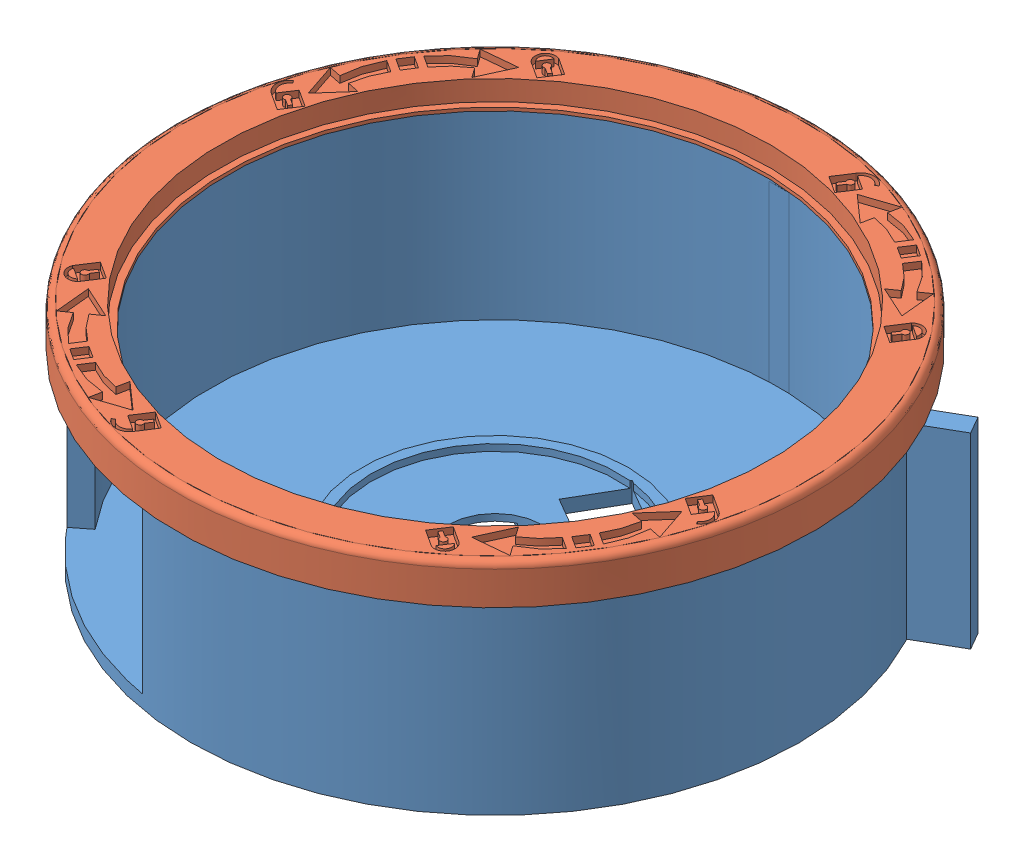
SolidWorks assembly shel ass, configuration Default. Lengths in mm.
Overall size (131.41 34.3 131.41).
2 component instances, 2 part files, 1 mates.
Components (placement in the parent):
- Shell 1 (blocks)-1: Shell 1 (blocks) [Default] at (21.3797 36.4662 93.1802) size (91.69 32 97.97)
- Shell lid 1 (blocks)-1: Shell lid 1 (blocks) [Default] at (21.3797 68.7692 93.1802) x (-0.544649 0 0.838664) z (-0.838664 0 -0.544649) size (95 6 95)
Mates (geometry in assembly coordinates):
- Concentric2: concentric: cylinder of Shell 1 (blocks)-1 through (21.3797 68.4662 93.1802) axis (0 -1 0) radius 45.5; cylinder of Shell lid 1 (blocks)-1 through (21.3797 70.7692 93.1802) axis (0 -1 0) radius 47.5
